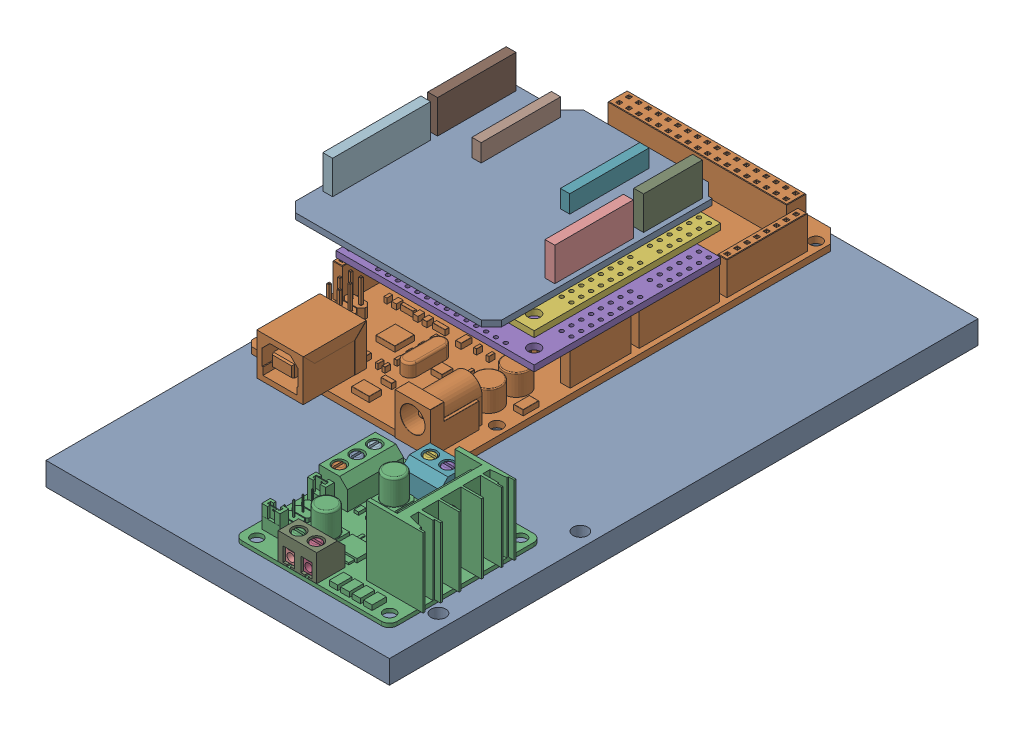
SolidWorks assembly Right_Saddle_Bag, configuration Default. Lengths in mm.
Overall size (88.9 41.71 152.4).
6 component instances, 5 part files, 19 mates.
Components (placement in the parent):
- Right_Saddle_Bag-1: Right_Saddle_Bag [Default] at (-67.4646 19.129 87.1857) size (88.9 5.99 152.4)
- ArduinoMega-1: ArduinoMega [Default] at (-39.4865 26.7744 -14.0587) x (0 0 1) z (0 -1 0) size (107.95 53.42 12.95)
- L298N-1: L298N [Default] at (-35.8664 8.646 71.9156) x (0 0 -1) z (1 0 0) size (39.39 19 41.67)
- dual-tb9051ftg-motor-driver-shield-2: dual-tb9051ftg-motor-driver-shield [Default] at (-13.8706 35.3342 14.3893) x (0 0 -1) z (0 1 0) size (48.26 51.31 7.68)
- dual-tb9051ftg-motor-driver-shield-3: dual-tb9051ftg-motor-driver-shield [Default] at (-13.8706 43.009 14.3893) x (0 0 -1) z (0 1 0) size (48.26 51.31 7.68)
- xbee shield-1: xbee shield [Default] at (-12.8546 51.4458 26.4543) x (0 0 -1) z (1 0 0) size (60.32 10.16 53.34)
Mates (geometry in assembly coordinates):
- Coincident5: coincident anti-aligned: plane of Right_Saddle_Bag-1 through (-67.4646 25.1234 87.1857) normal (0 1 0); plane of ArduinoMega-1 through (-12.7784 25.1234 36.7413) normal (0 -1 0)
- Concentric1: concentric aligned: cylinder of Right_Saddle_Bag-1 through (-63.6546 19.129 22.6189) axis (0 1 0) radius 1.905; cylinder of ArduinoMega-1 through (-63.6546 25.1224 22.6189) axis (0 1 0) radius 1.5621
- Coincident6: coincident anti-aligned: plane of Right_Saddle_Bag-1 through (-67.4646 25.1234 87.1857) normal (0 1 0); plane of L298N-1 through (-23.0658 25.1234 78.8357) normal (0 -1 0)
- Parallel2: parallel aligned: plane of Right_Saddle_Bag-1 through (-67.4646 25.1234 -65.2143) normal (0 0 -1); plane of L298N-1 through (13.0854 26.1234 41.4449) normal (0 0 -1)
- Distance1: distance = 6.35 mm aligned: plane of L298N-1 through (15.0854 26.1234 43.4449) normal (1 0 0); plane of Right_Saddle_Bag-1 through (21.4354 25.1234 -65.2143) normal (1 0 0)
- Distance2: distance = 6.35 mm aligned: plane of L298N-1 through (13.0854 26.1234 80.8357) normal (0 0 1); plane of Right_Saddle_Bag-1 through (-67.4646 25.1234 87.1857) normal (0 0 1)
- Parallel4: parallel aligned: plane of Right_Saddle_Bag-1 through (-67.4646 25.1234 -65.2143) normal (0 0 -1); plane of ArduinoMega-1 through (-66.1946 25.1234 -64.8587) normal (0 0 -1)
- Parallel6: parallel aligned: plane of Right_Saddle_Bag-1 through (-67.4646 25.1234 87.1857) normal (0 0 1); plane of dual-tb9051ftg-motor-driver-shield-2 through (-65.1786 36.909 14.3893) normal (0 0 1)
- Parallel7: parallel aligned: plane of Right_Saddle_Bag-1 through (-67.4646 19.129 87.1857) normal (0 -1 0); plane of dual-tb9051ftg-motor-driver-shield-2 through (-13.8706 35.3342 14.3893) normal (0 -1 0)
- Coincident16: coincident aligned: plane of ArduinoMega-1 through (-16.5884 35.3342 -33.8707) normal (0 0 -1); plane of dual-tb9051ftg-motor-driver-shield-2 through (-13.8706 36.909 -33.8707) normal (0 0 -1)
- Coincident17: coincident anti-aligned: plane of ArduinoMega-1 through (-14.1246 35.3342 -13.0427) normal (0 1 0); plane of dual-tb9051ftg-motor-driver-shield-2 through (-13.8706 35.3342 14.3893) normal (0 -1 0)
- Width1: width anti-aligned: plane of dual-tb9051ftg-motor-driver-shield-2 through (-13.8706 36.909 14.3893) normal (1 0 0); plane of ArduinoMega-1 through (-65.1786 36.909 -33.8707) normal (-1 0 0); plane of dual-tb9051ftg-motor-driver-shield-2 through (-64.9246 35.3342 -50.7363) normal (-1 0 0); plane of ArduinoMega-1 through (-14.1246 35.3342 -33.8707) normal (1 0 0)
- Concentric4: concentric aligned: cylinder of dual-tb9051ftg-motor-driver-shield-2 through (-17.6806 36.909 10.5793) axis (0 -1 0) radius 1.5875; cylinder of dual-tb9051ftg-motor-driver-shield-3 through (-17.6806 44.5838 10.5793) axis (0 -1 0) radius 1.5875
- Concentric5: concentric aligned: cylinder of dual-tb9051ftg-motor-driver-shield-2 through (-52.0246 36.909 -29.2987) axis (0 -1 0) radius 1.0922; cylinder of dual-tb9051ftg-motor-driver-shield-3 through (-52.0246 44.5838 -29.2987) axis (0 -1 0) radius 1.0922
- Coincident19: coincident anti-aligned: plane of dual-tb9051ftg-motor-driver-shield-2 through (-13.8706 43.009 14.3893) normal (0 1 0); plane of dual-tb9051ftg-motor-driver-shield-3 through (-13.8706 43.009 14.3893) normal (0 -1 0)
- Parallel8: parallel aligned: plane of dual-tb9051ftg-motor-driver-shield-3 through (-13.8706 44.5838 -33.8707) normal (0 0 -1); plane of xbee shield-1 through (-49.2876 52.2078 -33.8707) normal (0 0 -1)
- Coincident21: coincident anti-aligned: plane of dual-tb9051ftg-motor-driver-shield-3 through (-13.8706 50.6838 14.3893) normal (0 1 0); plane of xbee shield-1 through (-12.8546 50.6838 26.4543) normal (0 -1 0)
- Width2: width anti-aligned: plane of xbee shield-1 through (-12.8546 52.2078 23.9143) normal (1 0 0); plane of dual-tb9051ftg-motor-driver-shield-3 through (-66.1946 52.2078 23.9143) normal (-1 0 0); plane of xbee shield-1 through (-65.1786 44.5838 -33.8707) normal (-1 0 0); plane of dual-tb9051ftg-motor-driver-shield-3 through (-13.8706 44.5838 14.3893) normal (1 0 0)
- Coincident22: coincident aligned: plane of dual-tb9051ftg-motor-driver-shield-3 through (-13.8706 44.5838 -33.8707) normal (0 0 -1); plane of xbee shield-1 through (-49.2876 52.2078 -33.8707) normal (0 0 -1)
